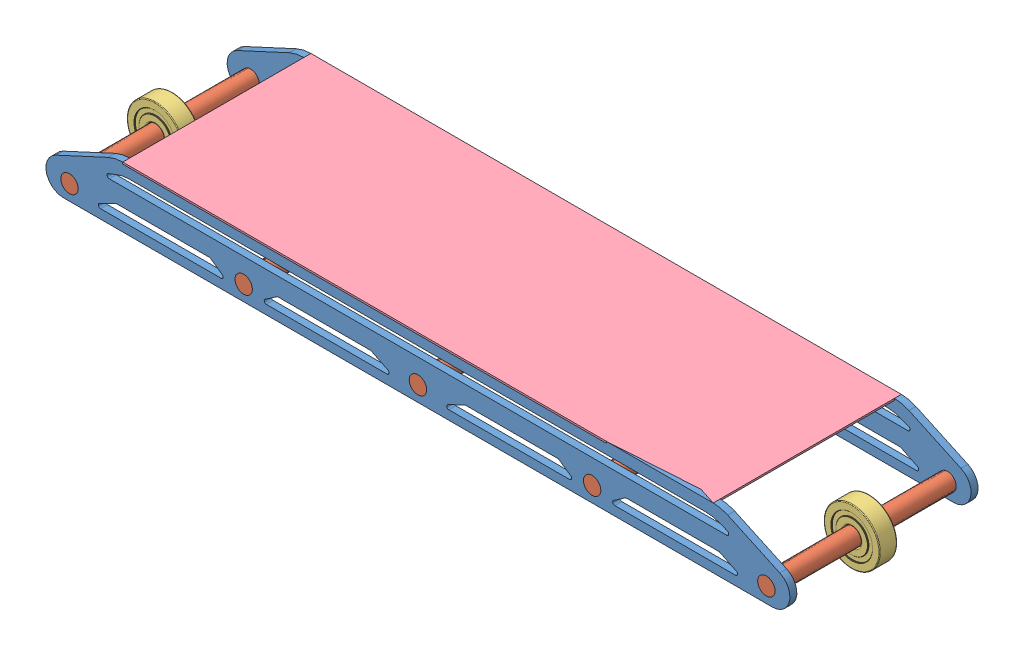
SolidWorks assembly Assem13, configuration Default. Lengths in mm.
Overall size (217.78 21.89 54).
11 component instances, 6 part files, 24 mates.
Components (placement in the parent):
- Part15-1: Part15 [Default] at (80.8262 113.9162 183.3485) size (213.52 17.38 2)
- Part16^Assem13-1: Part16^Assem13 [Default] at (80.8262 113.9162 183.3485) size (205 5.01 54) (virtual)
- Part15-2: Part15 [Default] at (80.8262 113.9162 235.3485) size (213.52 17.38 2)
- Part17^Assem13-1: Part17^Assem13 [Default] at (80.8262 113.9162 183.3485) x (-1 0 0) z (0 0 -1) (virtual)
- Part18^Assem13-1: Part18^Assem13 [Default] at origin (virtual)
- 5mm Bearing SKF 625 RS 286-7811-1: 5mm Bearing SKF 625 RS 286-7811 [Default] at (180.8262 113.9162 207.8485) x (0 0 -1) z (-0.993011 -0.118021 0) size (5 16 16)
- 5mm Bearing SKF 625 RS 286-7811-2: 5mm Bearing SKF 625 RS 286-7811 [Default] at (130.8262 113.9162 207.8485) x (0 0 -1) z (-0.993011 -0.118021 0) size (5 16 16)
- 5mm Bearing SKF 625 RS 286-7811-3: 5mm Bearing SKF 625 RS 286-7811 [Default] at (80.8262 113.9162 207.8485) x (0 0 -1) z (-0.993011 -0.118021 0) size (5 16 16)
- 5mm Bearing SKF 625 RS 286-7811-4: 5mm Bearing SKF 625 RS 286-7811 [Default] at (30.8262 113.9162 207.8485) x (0 0 -1) z (-0.993011 -0.118021 0) size (5 16 16)
- 5mm Bearing SKF 625 RS 286-7811-5: 5mm Bearing SKF 625 RS 286-7811 [Default] at (-19.1738 113.9162 207.8485) x (0 0 -1) z (-0.993011 -0.118021 0) size (5 16 16)
- Part19^Assem13-1: Part19^Assem13 [Default] at (80.8262 113.9162 237.3485) size (169.46 0.5 54) (virtual)
Mates (geometry in assembly coordinates):
- Concentric1: concentric aligned: circle of Part16^Assem1-1; circle of Part15-2
- Concentric2: concentric anti-aligned: circle of Part16^Assem1-1; circle of Part15-2
- Coincident4: coincident aligned: plane of Part16^Assem1-1 through (80.8262 113.9162 237.3485) normal (0 0 1); plane of Part15-2 through (80.8262 113.9162 237.3485) normal (0 0 1)
- Coincident5: coincident aligned: plane of Part15-1 through (80.8262 113.9162 183.3485) normal (0 0 -1); plane of Part16^Assem1-1 through (80.8262 113.9162 183.3485) normal (0 0 -1)
- InPlace2: in place: plane of ? through (180.8262 113.9162 183.3485) normal (0 0 -1); plane of ? through (0 0 183.3485) normal (0 0 -1); moOrthogonalPlaneRef_w of ? through (180.8262 113.9162 183.3485) normal (0 0 -1); plane of ? through (0 0 183.3485) normal (0 1 0); plane of ? through (180.8262 113.9162 183.3485) normal (0 0 -1); plane of ? through (0 0 183.3485) normal (-1 0 0); plane of ? through (180.8262 113.9162 183.3485) normal (0 0 -1); unknown of Part17^Assem13-1
- Coincident6: coincident aligned: plane of ?; plane of ?
- Coincident7: coincident aligned: moOrthogonalPlaneRef_w of Part16^Assem1-1 through (80.8262 113.9162 183.3485) normal (0 1 0); plane of Part17^Assem1-1 through (80.8262 113.9162 183.3485) normal (0 1 0)
- Coincident8: coincident anti-aligned: moOrthogonalPlaneRef_w of Part16^Assem1-1 through (80.8262 113.9162 183.3485) normal (1 0 0); plane of Part17^Assem1-1 through (80.8262 113.9162 183.3485) normal (-1 0 0)
- Concentric5: concentric anti-aligned: circle of Part16^Assem1-1; circle of 5mm Bearing SKF 625 RS 286-7811-1
- Concentric7: concentric aligned: circle of Part15-1; circle of Part16^Assem1-1
- Concentric8: concentric anti-aligned: circle of Part15-1; circle of Part16^Assem1-1
- Concentric9: concentric anti-aligned: circle of Part16^Assem1-1; circle of 5mm Bearing SKF 625 RS 286-7811-2
- Concentric10: concentric anti-aligned: circle of Part16^Assem1-1; circle of 5mm Bearing SKF 625 RS 286-7811-3
- Concentric11: concentric anti-aligned: circle of Part16^Assem1-1; circle of 5mm Bearing SKF 625 RS 286-7811-4
- Concentric12: concentric anti-aligned: circle of Part16^Assem1-1; circle of 5mm Bearing SKF 625 RS 286-7811-5
- Width1: width anti-aligned: plane of 5mm Bearing SKF 625 RS 286-7811-1 through (181.5314 107.983 207.8485) normal (0 0 -1); plane of 5mm Bearing SKF 625 RS 286-7811-1 through (181.5314 107.983 212.8485) normal (0 0 1); plane of Part15-1 through (80.8262 113.9162 185.3485) normal (0 0 1); plane of Part15-2 through (80.8262 113.9162 235.3485) normal (0 0 -1)
- Coincident11: coincident aligned: plane of 5mm Bearing SKF 625 RS 286-7811-1 through (181.5314 107.983 207.8485) normal (0 0 -1); plane of 5mm Bearing SKF 625 RS 286-7811-2 through (131.5314 107.983 207.8485) normal (0 0 -1)
- Coincident12: coincident aligned: plane of 5mm Bearing SKF 625 RS 286-7811-1 through (181.5314 107.983 207.8485) normal (0 0 -1); plane of 5mm Bearing SKF 625 RS 286-7811-3 through (81.5314 107.983 207.8485) normal (0 0 -1)
- Coincident13: coincident aligned: plane of 5mm Bearing SKF 625 RS 286-7811-1 through (181.5314 107.983 207.8485) normal (0 0 -1); plane of 5mm Bearing SKF 625 RS 286-7811-4 through (31.5314 107.983 207.8485) normal (0 0 -1)
- Coincident14: coincident aligned: plane of 5mm Bearing SKF 625 RS 286-7811-1 through (181.5314 107.983 207.8485) normal (0 0 -1); plane of 5mm Bearing SKF 625 RS 286-7811-5 through (-18.4686 107.983 207.8485) normal (0 0 -1)
- InPlace3: in place: plane of Part15-2 through (80.8262 113.9162 237.3485) normal (0 0 1); plane of ? through (0 0 237.3485) normal (0 0 1); plane of Part15-2 through (80.8262 113.9162 237.3485) normal (0 0 1); plane of ? through (0 0 237.3485) normal (0 1 0); plane of Part15-2 through (80.8262 113.9162 237.3485) normal (0 0 1); plane of ? through (0 0 237.3485) normal (1 0 0); plane of Part15-2 through (80.8262 113.9162 237.3485) normal (0 0 1); unknown of Part19^Assem13-1
- Coincident19: coincident aligned: plane of ?; plane of ?
- Coincident20: coincident aligned: moOrthogonalPlaneRef_w of Part15-2 through (80.8262 113.9162 237.3485) normal (0 1 0); plane of Part19^Assem13-1 through (80.8262 113.9162 237.3485) normal (0 1 0)
- Coincident21: coincident anti-aligned: moOrthogonalPlaneRef_w of Part15-2 through (80.8262 113.9162 237.3485) normal (-1 0 0); plane of Part19^Assem13-1 through (80.8262 113.9162 237.3485) normal (1 0 0)
